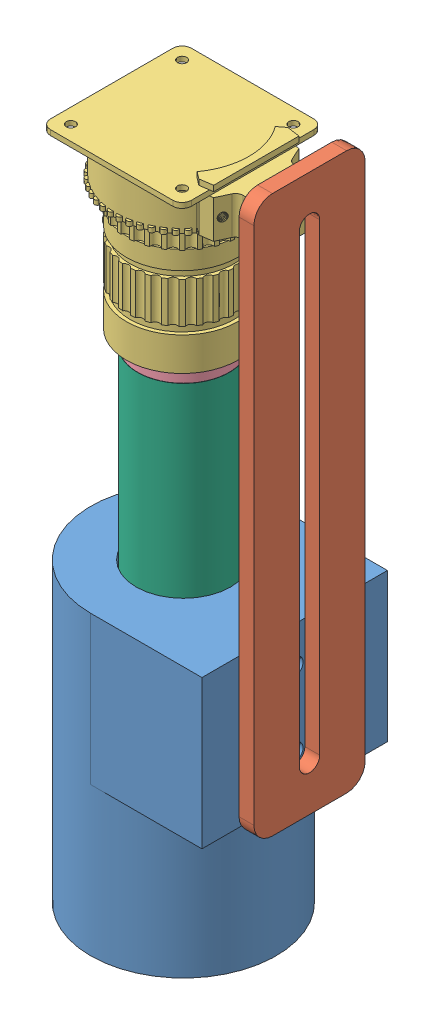
SolidWorks assembly spectrometer assembly, configuration Default. Lengths in mm.
Overall size (59 187.5 50).
7 component instances, 6 part files, 9 mates.
Components (placement in the parent):
- Spectrometer holder-1: Spectrometer holder [Default] at (27.216 -61.619 63.8815) x (1 0 0) z (0 0 -1) size (55 80 50)
- party plate-1: party plate [Default] at (61.216 -29.119 63.8815) x (0 1 0) z (0 0 1) size (150 4 30)
- Raspberry Pi HQ Camera with cs mount lens v3.step-1: Raspberry Pi HQ Camera with cs mount lens v3.step [Default] at (7.866 39.881 44.8815) x (0 0 1) z (1 0 0) size (38 49.1 51.85)
- spectroscope-1: spectroscope [Default] at (31.3077 -17.4856 46.942) x (0.894261 0 0.447545) z (-0.447545 0 0.894261) size (24.75 104 24.75)
  - back-1: back [Default] at (3.9221 5.7665 16.9796) size (24.6 8.5 24.6)
  - front-1: front [Default] at (3.9221 -89.7335 16.9796) size (24.65 5.5 24.65)
  - middle-1: middle [Default] at (3.9221 -84.2335 16.9796) size (24.75 90 24.75)
Mates (geometry in assembly coordinates):
- Coincident2: coincident anti-aligned: plane of Spectrometer holder-1 through (57.216 -61.619 63.8815) normal (1 0 0); plane of party plate-1 through (57.216 -29.119 63.8815) normal (-1 0 0)
- Slot3: slot aligned: cylinder of Spectrometer holder-1 through (47.216 -91.619 63.8815) axis (1 0 0) radius 2.25; plane of party plate-1 through (57.216 -91.619 61.1315) normal (0 0 1); cylinder of party plate-1 through (57.216 33.381 63.8815) axis (1 0 0) radius 2.75
- Slot4: slot aligned: cylinder of Spectrometer holder-1 through (47.216 -71.619 63.8815) axis (1 0 0) radius 2.25; plane of party plate-1 through (57.216 -91.619 61.1315) normal (0 0 1); cylinder of party plate-1 through (57.216 33.381 63.8815) axis (1 0 0) radius 2.75
- Coincident3: coincident anti-aligned: plane of party plate-1 through (57.216 -29.119 63.8815) normal (-1 0 0); plane of Raspberry Pi HQ Camera with cs mount lens v3.step-1 through (57.216 38.481 56.8965) normal (1 0 0)
- Slot5: slot anti-aligned: plane of party plate-1 through (57.216 -91.619 61.1315) normal (0 0 1); cylinder of Raspberry Pi HQ Camera with cs mount lens v3.step-1 through (57.216 33.381 63.8815) axis (-1 0 0) radius 2.117; cylinder of party plate-1 through (57.216 33.381 63.8815) axis (1 0 0) radius 2.75
- Concentric1: concentric aligned: cylinder of Spectrometer holder-1 through (27.216 -61.619 63.8815) axis (0 -1 0) radius 12.75; cylinder of spectroscope-1/middle-1 through (27.216 -11.719 63.8815) axis (0 -1 0) radius 12.375
- Coincident4: coincident anti-aligned: plane of Raspberry Pi HQ Camera with cs mount lens v3.step-1 through (26.866 -3.219 63.8815) normal (0 -1 0); plane of spectroscope-1/back-1 through (27.216 -3.219 63.8815) normal (0 1 0)
- Parallel1: parallel aligned: cylinder of Spectrometer holder-1 through (27.216 -61.619 63.8815) axis (0 -1 0) radius 12.75; cylinder of spectroscope-1/middle-1 through (27.216 -11.719 63.8815) axis (0 -1 0) radius 12.375
- LimitDistance1: limit distance = 77.9 mm anti-aligned: plane of Raspberry Pi HQ Camera with cs mount lens v3.step-1 through (26.866 16.281 63.8815) normal (0 -1 0); plane of Spectrometer holder-1 through (27.216 -61.619 63.8815) normal (0 1 0)
